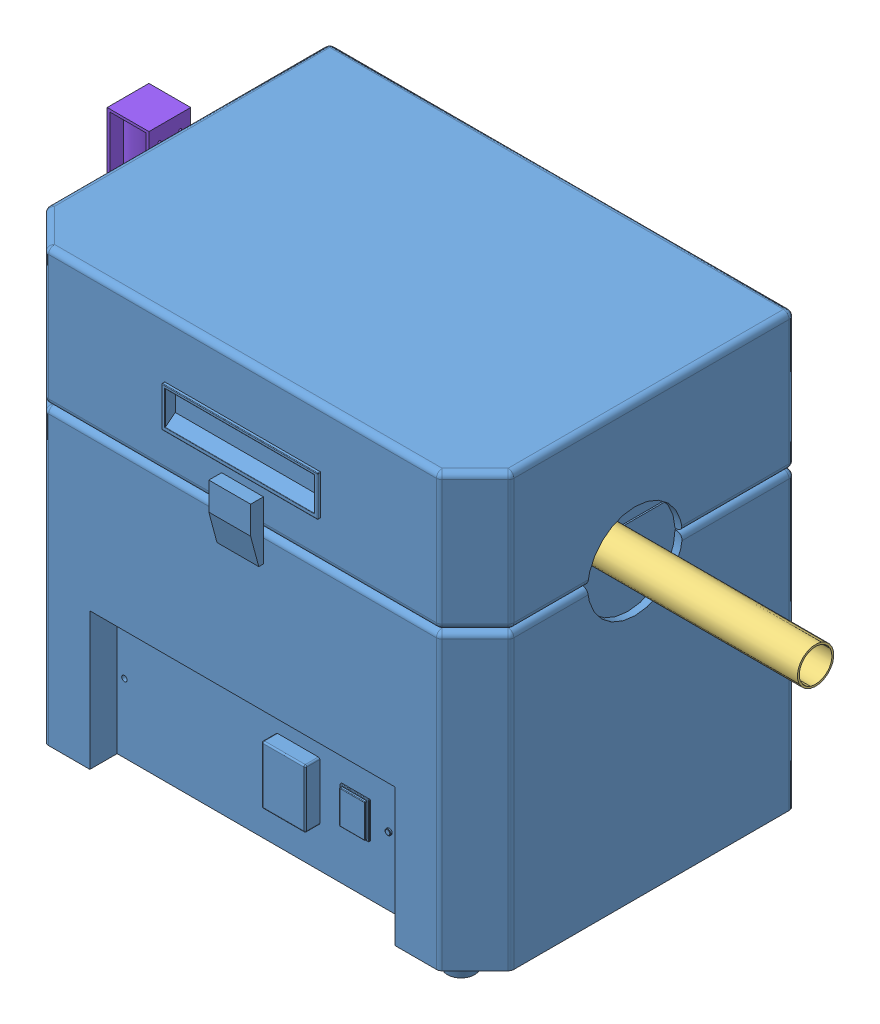
SolidWorks assembly Furnace Assembly, configuration Upper. Lengths in mm.
Overall size (600.64 399.61 295.75).
24 component instances, 8 part files, 11 mates.
Components (placement in the parent):
- furnace-1: furnace [Default] at (154.2459 140.3605 359.3287) size (406.4 389.37 295.15)
- binding head screw_ai-15: binding head screw_ai [CR-BHMS 0.164-36x0.188x0.188-N] at (281.2459 409.7123 214.4217) x (0 0 1) z (-1 0 0) size (7.41 8.74 8.74)
- binding head screw_ai-29: binding head screw_ai [CR-BHMS 0.164-36x0.188x0.188-N] at (281.2459 384.3123 214.4217) x (0 0 1) z (-1 0 0) size (7.41 8.74 8.74)
- binding head screw_ai-30: binding head screw_ai [CR-BHMS 0.164-36x0.188x0.188-N] at (230.4459 409.7123 214.4217) x (0 0 1) z (-1 0 0) size (7.41 8.74 8.74)
- binding head screw_ai-31: binding head screw_ai [CR-BHMS 0.164-36x0.188x0.188-N] at (230.4459 384.3123 214.4217) x (0 0 1) z (-1 0 0) size (7.41 8.74 8.74)
- binding head screw_ai-32: binding head screw_ai [CR-BHMS 0.164-36x0.188x0.188-N] at (179.6459 409.7123 214.4217) x (0 0 1) z (-1 0 0) size (7.41 8.74 8.74)
- binding head screw_ai-33: binding head screw_ai [CR-BHMS 0.164-36x0.188x0.188-N] at (179.6459 384.3123 214.4217) x (0 0 1) z (-1 0 0) size (7.41 8.74 8.74)
- binding head screw_ai-34: binding head screw_ai [CR-BHMS 0.164-36x0.188x0.188-N] at (128.8459 409.7123 214.4217) x (0 0 1) z (-1 0 0) size (7.41 8.74 8.74)
- binding head screw_ai-35: binding head screw_ai [CR-BHMS 0.164-36x0.188x0.188-N] at (128.8459 384.3123 214.4217) x (0 0 1) z (-1 0 0) size (7.41 8.74 8.74)
- binding head screw_ai-36: binding head screw_ai [CR-BHMS 0.164-36x0.188x0.188-N] at (78.0459 409.7123 214.4217) x (0 0 1) z (-1 0 0) size (7.41 8.74 8.74)
- binding head screw_ai-37: binding head screw_ai [CR-BHMS 0.164-36x0.188x0.188-N] at (78.0459 384.3123 214.4217) x (0 0 1) z (-1 0 0) size (7.41 8.74 8.74)
- binding head screw_ai-38: binding head screw_ai [CR-BHMS 0.164-36x0.188x0.188-N] at (27.2459 409.7123 214.4217) x (0 0 1) z (-1 0 0) size (7.41 8.74 8.74)
- binding head screw_ai-39: binding head screw_ai [CR-BHMS 0.164-36x0.188x0.188-N] at (27.2459 384.3123 214.4217) x (0 0 1) z (-1 0 0) size (7.41 8.74 8.74)
- Quartz Tube-1: Quartz Tube [Default] at (-62.664 396.3773 359.3287) x (0 -0.831575 0.555412) z (0 0.555412 0.831575) size (31.75 577.85 31.75)
- Gate Assembly-1: Gate Assembly [Closed] at (-10.7914 350.4727 325.377) x (0 0 1) z (-1 0 0) size (63.5 261.79 36.5)
  - Gate Guidance Slot-1: Gate Guidance Slot [Default] at (-0.3235 -21.7408 -27.2374) size (63.5 76.2 19.08)
    - gate slot_1-1: gate slot_1 [Default] at (2.5253 29.5453 79.11) size (63.5 76.2 13.56)
    - gate slot_2-1: gate slot_2 [Default] at (66.0253 29.5453 85.65) x (0 1 0) z (0 0 1) size (76.2 63.5 6.54)
  - Gate-1: Gate [Default] at (8.9517 6.1316 58.4126) x (0 1 0) z (0 0 -1) size (70 50 4.06)
  - Solenoid Rod-1: Solenoid Rod [Default] at (33.9517 -34.1884 56.4126) x (1 0 0) z (0 1 0) size (11.1 11.1 50.8)
  - Solenoid-1: Solenoid [Default] at (15.7018 -34.1884 74.6625) x (0 -1 0) z (1 0 0) size (50.8 36.5 36.5)
  - Solenoid-2: Solenoid [Default] at (52.2016 125.9975 74.6625) x (0 1 0) z (-1 0 0) size (50.8 36.5 36.5)
  - Solenoid Rod-2: Solenoid Rod [Default] at (33.9517 125.9975 56.4126) x (1 0 0) z (0 -1 0) size (11.1 11.1 50.8)
  - Gate-2: Gate [Default] at (8.9517 85.6775 54.4766) x (0 -1 0) z (0 0 1) size (70 50 4.06)
Mates (geometry in assembly coordinates):
- Concentric1: concentric aligned: cylinder of furnace-1 through (281.2459 409.7123 217.0887) axis (0 0 -1) radius 2.3813; cylinder of binding head screw_ai-15 through (281.2459 409.7123 189.0217) axis (0 0 -1) radius 2.0828
- Coincident1: coincident anti-aligned: plane of furnace-1 through (154.2459 140.3605 217.0887) normal (0 0 -1); plane of binding head screw_ai-15 through (281.2459 411.7951 217.0887) normal (0 0 1)
- Parallel2: parallel aligned: line of furnace-1 through (-10.8541 422.4123 217.0887) axis (1 0 0); line of binding head screw_ai-15 through (280.9665 409.9917 217.6221) axis (1 0 0)
- Concentric2: concentric anti-aligned: cylinder of furnace-1 through (-48.9541 396.3773 359.3287) axis (1 0 0) radius 15.875; cylinder of Quartz Tube-1 through (515.186 396.3773 359.3287) axis (-1 0 0) radius 15.875
- Coincident3: coincident anti-aligned: plane of furnace-1 through (357.4459 517.0273 499.0287) normal (1 0 0); plane of Gate Assembly-1/Solenoid-1 through (357.4459 316.2843 341.0788) normal (-1 0 0)
- Concentric3: concentric anti-aligned: cylinder of Quartz Tube-1 through (371.1558 396.3773 359.3287) axis (-1 0 0) radius 15.875; cylinder of Gate Assembly-1/Gate Guidance Slot-1/gate slot_1-1 through (361.1558 396.3773 359.3287) axis (1 0 0) radius 16
- Coincident4: coincident anti-aligned: plane of Quartz Tube-1 through (371.1558 396.3773 359.3287) normal (1 0 0); plane of Gate Assembly-1/Gate Guidance Slot-1/gate slot_1-1 through (371.1558 358.2773 391.0787) normal (-1 0 0)
- Parallel3: parallel aligned: plane of furnace-1 through (154.2459 140.3605 359.3287) normal (0 -1 0); plane of Gate Assembly-1/Solenoid-1 through (-85.4539 265.4843 377.5786) normal (0 -1 0)
- Coincident5: coincident anti-aligned: plane of furnace-1 through (-48.9541 517.0273 499.0287) normal (-1 0 0); plane of Gate Assembly-1/Solenoid-1 through (-48.9541 316.2843 377.5786) normal (1 0 0)
- Coincident6: coincident anti-aligned: plane of Quartz Tube-1 through (-62.664 396.3773 359.3287) normal (-1 0 0); plane of Gate Assembly-1/Gate Guidance Slot-1/gate slot_1-1 through (-62.664 358.2773 327.5787) normal (1 0 0)
- Concentric6: concentric aligned: cylinder of Quartz Tube-1 through (515.186 396.3773 359.3287) axis (-1 0 0) radius 15.875; cylinder of Gate Assembly-1/Gate Guidance Slot-1/gate slot_1-1 through (-52.664 396.3773 359.3287) axis (-1 0 0) radius 16
